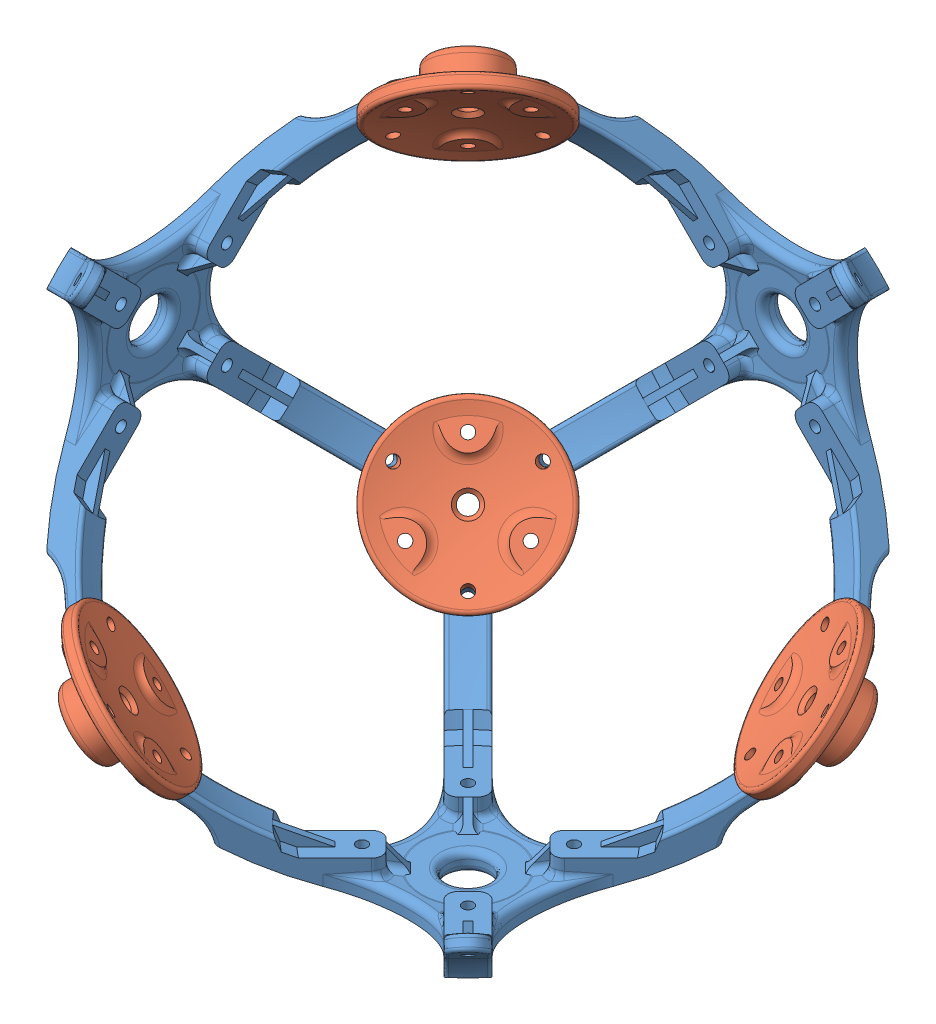
SolidWorks assembly 总装配体-半边, configuration 默认. Lengths in mm.
Overall size (192.55 192.55 192.55).
7 component instances, 2 part files, 16 mates.
Components (placement in the parent):
- 内部支撑架-连点-1: 内部支撑架-连点 [默认] at (176.0355 -33.2484 -26.2351) x (0.707107 0 -0.707107) z (0.707107 0 0.707107) size (133.98 34.75 133.98)
- 内部支撑架-连点-2: 内部支撑架-连点 [默认] at (176.0355 -33.2484 -26.2351) x (0 -0.707107 -0.707107) z (0 -0.707107 0.707107) size (133.98 34.75 133.98)
- 内部支撑架-连点-3: 内部支撑架-连点 [默认] at (176.0355 -33.2484 -26.2351) x (0.707107 0.707107 0) z (0.707107 -0.707107 0) size (133.98 34.75 133.98)
- 内部支撑架-桥接点-1: 内部支撑架-桥接点 [默认] at (176.0355 -33.2484 -26.2351) x (0.707107 -0.707107 0) z (-0.408248 -0.408248 0.816497) size (46 14.77 46)
- 内部支撑架-桥接点-2: 内部支撑架-桥接点 [默认] at (176.0355 -33.2484 -26.2351) x (0.707107 0 0.707107) z (-0.408248 0.816496 0.408248) size (46 14.77 46)
- 内部支撑架-桥接点-3: 内部支撑架-桥接点 [默认] at (176.0355 -33.2484 -26.2351) x (0.707107 0.707107 0) z (0.408248 -0.408248 0.816496) size (46 14.77 46)
- 内部支撑架-桥接点-4: 内部支撑架-桥接点 [默认] at (176.0355 -33.2484 -26.2351) x (0.707107 0 -0.707107) z (-0.408248 -0.816497 -0.408248) size (46 14.77 46)
Mates (geometry in assembly coordinates):
- 同心32: concentric aligned: cylinder of 内部支撑架-连点-3 through (119.5566 -89.7273 -112.685) axis (0.479854 0.479854 0.734493) radius 1.6; cylinder of 内部支撑架-桥接点-1 through (125.5619 -83.7219 -103.4928) axis (0.479854 0.479854 0.734493) radius 1.6
- 同心33: concentric aligned: cylinder of 内部支撑架-连点-2 through (89.5856 -89.7273 -82.714) axis (0.734493 0.479854 0.479854) radius 1.6; cylinder of 内部支撑架-桥接点-1 through (96.2624 -85.3652 -78.3519) axis (0.734493 0.479854 0.479854) radius 1.6
- 同心34: concentric aligned: cylinder of 内部支撑架-连点-1 through (119.5566 -119.6983 -82.714) axis (0.479854 0.734493 0.479854) radius 1.6; cylinder of 内部支撑架-桥接点-1 through (123.9186 -113.0214 -78.3519) axis (0.479854 0.734493 0.479854) radius 1.6
- 同心35: concentric: sphere of 内部支撑架-桥接点-1; sphere of 球壳示意-3
- 同心36: concentric: sphere of 内部支撑架-连点-3; sphere of 球壳示意-3
- 同心37: concentric: sphere of 内部支撑架-连点-1; sphere of 球壳示意-3
- 同心38: concentric: sphere of 内部支撑架-连点-2; sphere of 球壳示意-3
- 同心39: concentric aligned: cylinder of 内部支撑架-桥接点-1 through (119.4551 -89.8287 -82.8154) axis (0.57735 0.57735 0.57735) radius 2.425; circle of 球壳示意-3
- 同心41: concentric aligned: cylinder of 内部支撑架-连点-2 through (89.5856 -89.7273 30.2438) axis (0.734493 0.479854 -0.479854) radius 1.6; cylinder of 内部支撑架-桥接点-2 through (96.2624 -85.3652 25.8817) axis (0.734493 0.479854 -0.479854) radius 1.6
- 同心42: concentric aligned: cylinder of 内部支撑架-连点-1 through (119.5566 -119.6983 30.2438) axis (0.479854 0.734493 -0.479854) radius 1.6; cylinder of 内部支撑架-桥接点-2 through (125.5619 -110.5061 24.2384) axis (0.479854 0.734493 -0.479854) radius 1.6
- 同心43: concentric aligned: cylinder of 内部支撑架-连点-2 through (89.5855 23.2305 -82.714) axis (0.734493 -0.479854 0.479854) radius 1.6; cylinder of 内部支撑架-桥接点-4 through (96.2624 18.8684 -78.3519) axis (0.734493 -0.479854 0.479854) radius 1.6
- 同心44: concentric aligned: cylinder of 内部支撑架-连点-3 through (119.5565 23.2305 -112.685) axis (0.479854 -0.479854 0.734493) radius 1.6; cylinder of 内部支撑架-桥接点-4 through (123.9186 18.8684 -106.0081) axis (0.479854 -0.479854 0.734493) radius 1.6
- 同心45: concentric aligned: cylinder of 内部支撑架-连点-3 through (232.5143 -89.7273 -112.685) axis (-0.479854 0.479854 0.734493) radius 1.6; cylinder of 内部支撑架-桥接点-3 through (226.509 -83.7219 -103.4928) axis (-0.479854 0.479854 0.734493) radius 1.6
- 同心46: concentric aligned: cylinder of 内部支撑架-连点-1 through (232.5143 -119.6983 -82.714) axis (-0.479854 0.734493 0.479854) radius 1.6; cylinder of 内部支撑架-桥接点-3 through (228.1523 -113.0214 -78.3519) axis (-0.479854 0.734493 0.479854) radius 1.6
- 重合1: coincident anti-aligned: plane of 球壳示意-3 through (176.0355 -33.2484 -26.2351) normal (0.57735 0.57735 0.57735); plane of 球壳示意-4 through (176.0355 -33.2484 -26.2351) normal (-0.57735 -0.57735 -0.57735)
- 同心47: concentric: sphere of 球壳示意-3; sphere of 球壳示意-4
